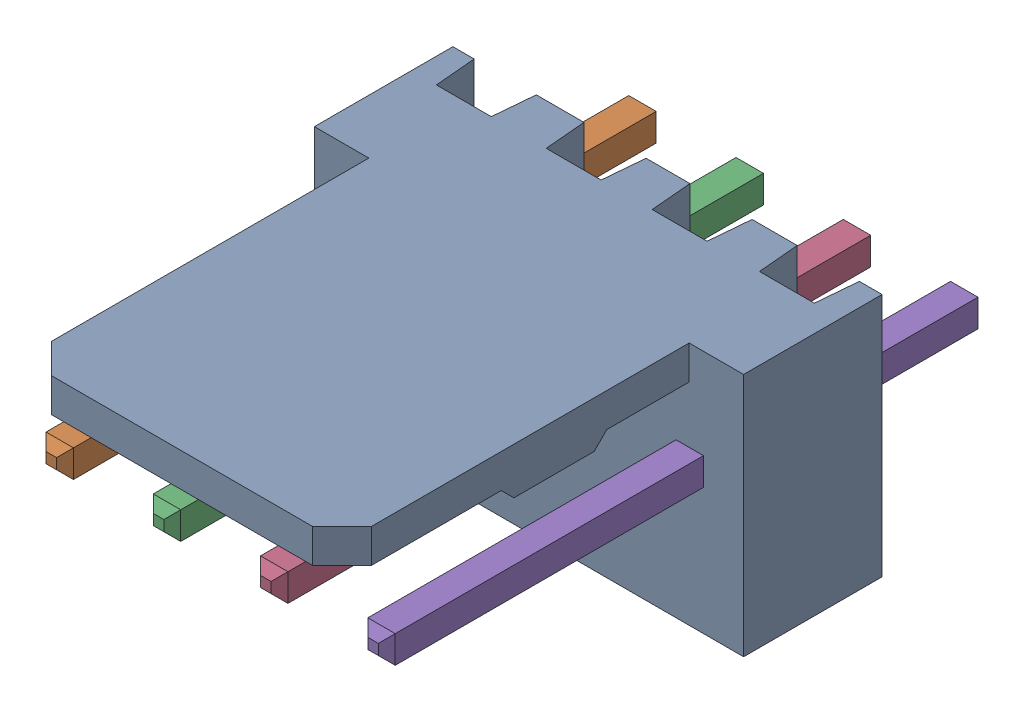
SolidWorks assembly Molex PCB 4 pin v3_2, configuration Default. Lengths in mm.
Overall size (10.16 5.79 14.92).
5 component instances, 2 part files, 0 mates.
Components (placement in the parent):
- BASE9710016-1: BASE9710016 [Default] at (2.54 2.895 -8.22) size (10.16 5.79 11.5)
- PINO9710016-1: PINO9710016 [Default] at (1.27 3.325 -0.72) size (0.65 0.65 14.2)
- PINO9710016-2: PINO9710016 [Default] at (3.81 3.325 -0.72) size (0.65 0.65 14.2)
- PINO9710016-3: PINO9710016 [Default] at (6.35 3.325 -0.72) size (0.65 0.65 14.2)
- PINO9710016-4: PINO9710016 [Default] at (8.89 3.325 -0.72) size (0.65 0.65 14.2)
